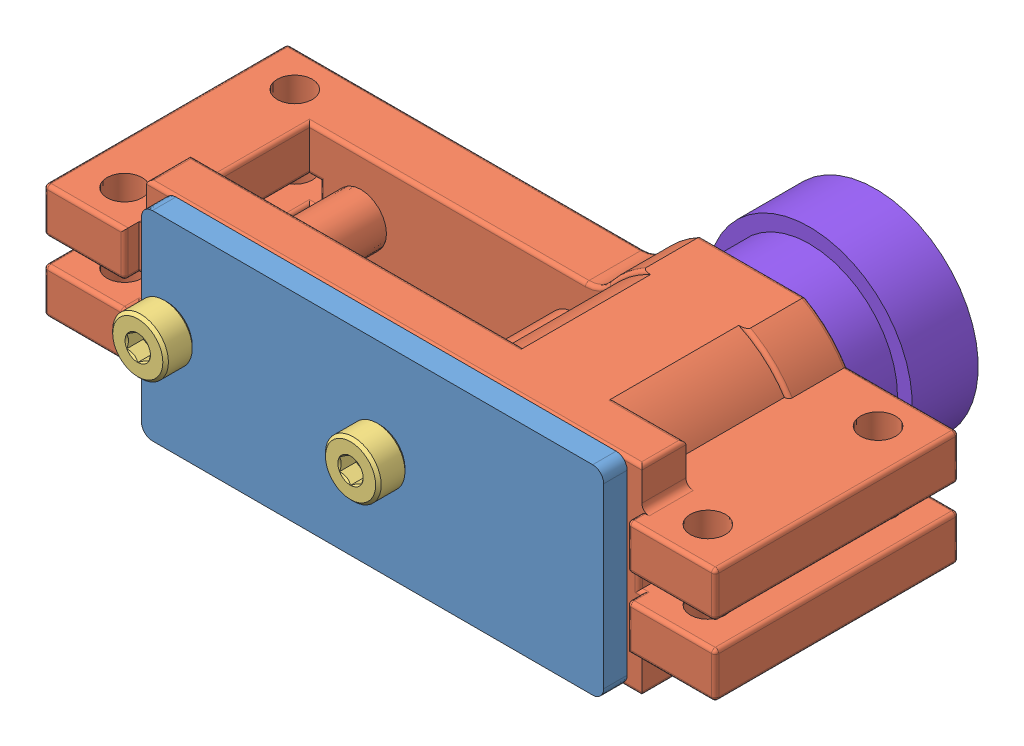
SolidWorks assembly startracker, configuration Default. Lengths in mm.
Overall size (45.75 14.75 27.61).
10 component instances, 8 part files, 55 mates.
Components (placement in the parent):
- startrackerboard-1: startrackerboard [Default] at (0 -0.2 2.3) x (-1 0 0) z (0 0 -1) size (31.5 13.6 1.6)
- startrackerboardmount-1: startrackerboardmount [Default] x (-1 0 0) z (0 0 1) size (45.75 14.75 16.6)
- 92290A850_SUPER-CORROSION-RST 316 SS SCKT HEAD SCREW-1: 92290A850_SUPER-CORROSION-RST 316 SS SCKT HEAD SCREW [92290A850] at (0.5 0 -14.9) x (1 0 0) z (0 0 -1) size (3.8 3.8 20.17)
- 92290A850_SUPER-CORROSION-RST 316 SS SCKT HEAD SCREW-2: 92290A850_SUPER-CORROSION-RST 316 SS SCKT HEAD SCREW [92290A850] at (-14 0 -14.9) x (-1 0 0) z (0 0 -1) size (3.8 3.8 20.17)
- 94150A115_316 STAINLESS STEEL HEX NUT-1: 94150A115_316 STAINLESS STEEL HEX NUT [94150A115] at (0.5 0 -13.05) x (-0.5 0.866025 0) z (0 0 1) size (3.2 3.7 1.58)
- 94150A115_316 STAINLESS STEEL HEX NUT-2: 94150A115_316 STAINLESS STEEL HEX NUT [94150A115] at (-14 0 -13.05) x (0.5 0.866025 0) z (0 0 1) size (3.2 3.7 1.58)
- ILCC48-1: ILCC48 [Default] at (8.75 0 1.5) x (-1 0 0) z (0 0 -1) size (4.8 3.6 0.72)
- knifeedgebaffle-1: knifeedgebaffle [Default] at (8.75 0 -6.425) x (0 1 0) z (1 0 0) size (12 2 12)
- ILCC48_cover-1: ILCC48_cover [Default] at (8.75 0 0.25) x (0 1 0) z (0 0 1) size (7 7 1.25)
- startrackerNEW-1: startrackerNEW [Default] at (8.75 0 -20.925) x (-1 0 0) z (0 0 -1) size (14 14 16)
Mates (geometry in assembly coordinates):
- Parallel1: parallel anti-aligned: plane of startrackerM12-1 through (8.75 0 -7.7) normal (-1 0 0); plane of startrackerboardmount-1 through (22.75 0 9.2082) normal (1 0 0)
- Concentric7: concentric aligned: circle of startrackerboard-1; circle of 92290A850_SUPER-CORROSION-RST 316 SS SCKT HEAD SCREW-1
- Concentric8: concentric aligned: circle of startrackerboard-1; circle of 92290A850_SUPER-CORROSION-RST 316 SS SCKT HEAD SCREW-2
- Parallel2: parallel anti-aligned: plane of startrackerboardmount-1 through (-17 3.9 1.5) normal (0 1 0); plane of 92290A850_SUPER-CORROSION-RST 316 SS SCKT HEAD SCREW-1 through (0.5 0 -14.9) normal (0 -1 0)
- Parallel3: parallel aligned: plane of startrackerboardmount-1 through (-17 3.9 1.5) normal (0 1 0); plane of 92290A850_SUPER-CORROSION-RST 316 SS SCKT HEAD SCREW-2 through (-14 0 -14.9) normal (0 1 0)
- Distance1: distance = 8.6 mm aligned: plane of startrackerM12-1 through (8.75 0 -21.7) normal (0 0 -1); plane of startrackerboardmount-1 through (8.75 0 -13.1) normal (0 0 -1)
- Concentric11: concentric anti-aligned: circle of startrackerM12-1; circle of startrackerboardmount-1
- Coincident17: coincident anti-aligned: plane of startrackerboardmount-1 through (0 0 0) normal (0 -1 0); plane of 91732A183_SPARK PLUG THREAD REPAIR KIT-2 through (0.5 0 1.5) normal (0 1 0)
- Coincident18: coincident anti-aligned: plane of startrackerboardmount-1 through (0 0 1.5) normal (0 0 1); plane of 91732A183_SPARK PLUG THREAD REPAIR KIT-2 through (0.5 0 1.5) normal (0 0 -1)
- Coincident21: coincident: point of startrackerboardmount-1; plane of 91732A183_SPARK PLUG THREAD REPAIR KIT-2 through (0.5 0 1.5) normal (1 0 0)
- Coincident22: coincident anti-aligned: plane of startrackerboardmount-1 through (0 0 1.5) normal (0 0 1); plane of 91732A183_SPARK PLUG THREAD REPAIR KIT-1 through (-14 0 1.5) normal (0 0 -1)
- Coincident23: coincident aligned: plane of startrackerboardmount-1 through (0 0 0) normal (0 -1 0); plane of 91732A183_SPARK PLUG THREAD REPAIR KIT-1 through (-14 0 1.5) normal (0 -1 0)
- Coincident24: coincident: point of startrackerboardmount-1; plane of 91732A183_SPARK PLUG THREAD REPAIR KIT-1 through (-14 0 1.5) normal (-1 0 0)
- Coincident26: coincident anti-aligned: plane of startrackerboardmount-1 through (8.75 0 -13.1) normal (0 0 -1); plane of 91732A183_SPARK PLUG THREAD REPAIR KIT-3 through (0.5 0 -13.1) normal (0 0 1)
- Coincident27: coincident: point of startrackerboardmount-1; plane of 91732A183_SPARK PLUG THREAD REPAIR KIT-3 through (0.5 0 -13.1) normal (-1 0 0)
- Coincident28: coincident: point of startrackerboardmount-1; plane of 91732A183_SPARK PLUG THREAD REPAIR KIT-3 through (0.5 0 -13.1) normal (0 1 0)
- Parallel4: parallel anti-aligned: plane of startrackerboardmount-1 through (-20 -3.9 1.5) normal (0 -1 0); plane of 91732A183_SPARK PLUG THREAD REPAIR KIT-3 through (0.5 0 -13.1) normal (0 1 0)
- Coincident29: coincident anti-aligned: plane of startrackerboardmount-1 through (8.75 0 -13.1) normal (0 0 -1); plane of 91732A183_SPARK PLUG THREAD REPAIR KIT-4 through (-14 0 -13.1) normal (0 0 1)
- Coincident30: coincident: point of startrackerboardmount-1; plane of 91732A183_SPARK PLUG THREAD REPAIR KIT-4 through (-14 0 -13.1) normal (-1 0 0)
- Coincident31: coincident: point of startrackerboardmount-1; plane of 91732A183_SPARK PLUG THREAD REPAIR KIT-4 through (-14 0 -13.1) normal (0 1 0)
- Parallel5: parallel anti-aligned: plane of startrackerboardmount-1 through (-20 -3.9 1.5) normal (0 -1 0); plane of 91732A183_SPARK PLUG THREAD REPAIR KIT-4 through (-14 0 -13.1) normal (0 1 0)
- Coincident32: coincident anti-aligned: plane of startrackerboardmount-1 through (0 0 0) normal (0 -1 0)
- Coincident33: coincident anti-aligned: plane of startrackerboardmount-1 through (0 0 0) normal (-1 0 0)
- Coincident34: coincident aligned: plane of startrackerboardmount-1 through (0 0 0) normal (0 0 1)
- Coincident35: coincident anti-aligned: plane of startrackerboard-1 through (15 5.85 1.5) normal (0 0 -1); plane of startrackerboardmount-1 through (0 0 1.5) normal (0 0 1)
- Coincident36: coincident aligned: plane of startrackerboard-1 through (15 6.6 1.5) normal (0 1 0); plane of startrackerboardmount-1 through (-17 6.6 -14.1) normal (0 1 0)
- Coincident38: coincident anti-aligned: plane of startrackerboard-1 through (15 5.85 3.1) normal (0 0 1); plane of 92290A850_SUPER-CORROSION-RST 316 SS SCKT HEAD SCREW-2 through (-14 0 3.1) normal (0 0 -1)
- Coincident39: coincident anti-aligned: plane of startrackerboard-1 through (15 5.85 3.1) normal (0 0 1); plane of 92290A850_SUPER-CORROSION-RST 316 SS SCKT HEAD SCREW-1 through (0.5 0 3.1) normal (0 0 -1)
- Coincident40: coincident aligned: plane of startrackerboard-1 through (0 -0.2 2.3) normal (-1 0 0); plane of startrackerboardmount-1 through (0 0 0) normal (-1 0 0)
- Concentric12: concentric anti-aligned: circle of 92290A850_SUPER-CORROSION-RST 316 SS SCKT HEAD SCREW-1; circle of 94150A115_316 STAINLESS STEEL HEX NUT-1
- Concentric13: concentric anti-aligned: circle of 92290A850_SUPER-CORROSION-RST 316 SS SCKT HEAD SCREW-2; circle of 94150A115_316 STAINLESS STEEL HEX NUT-2
- Coincident42: coincident anti-aligned: plane of startrackerboardmount-1 through (0 0 -12.4) normal (0 0 -1); plane of 94150A115_316 STAINLESS STEEL HEX NUT-1 through (0.5 -1.8475 -12.4) normal (0 0 1)
- Parallel6: parallel aligned: plane of 94150A115_316 STAINLESS STEEL HEX NUT-1 through (-1.1 0.9238 -12.4) normal (-1 0 0); plane of startrackerboardmount-1 through (-23 0 16.7315) normal (-1 0 0)
- Parallel7: parallel aligned: plane of 94150A115_316 STAINLESS STEEL HEX NUT-2 through (-15.6 0.9238 -12.4) normal (-1 0 0); plane of startrackerboardmount-1 through (-23 0 16.7315) normal (-1 0 0)
- Coincident43: coincident aligned: plane of startrackerM12-1 through (8.75 0 -7.7) normal (-1 0 0); plane of ILCC48-1 through (8.75 0 1.5) normal (-1 0 0)
- Coincident44: coincident anti-aligned: plane of startrackerM12-1 through (8.75 0 -7.7) normal (0 -1 0); plane of ILCC48-1 through (8.75 0 1.5) normal (0 1 0)
- Coincident45: coincident anti-aligned: plane of startrackerboard-1 through (15 5.85 1.5) normal (0 0 -1); plane of ILCC48-1 through (8.75 0 1.5) normal (0 0 1)
- Coincident46: coincident anti-aligned: plane of startrackerM12-1 through (8.75 0 -7.7) normal (0 -1 0); plane of knifeedgebaffle-1 through (8.75 0 -6.425) normal (0 1 0)
- Coincident47: coincident anti-aligned: plane of startrackerM12-1 through (8.75 0 -7.7) normal (-1 0 0); plane of knifeedgebaffle-1 through (8.75 0 -6.425) normal (1 0 0)
- Coincident48: coincident anti-aligned: plane of startrackerboardmount-1 through (8.75 0 -4.425) normal (0 0 -1); plane of knifeedgebaffle-1 through (8.75 0 -4.425) normal (0 0 1)
- Coincident49: coincident anti-aligned: plane of startrackerM12-1 through (8.75 0 -7.7) normal (0 -1 0); plane of ILCC48_cover-1 through (8.75 0 0.25) normal (0 1 0)
- Coincident50: coincident aligned: plane of startrackerM12-1 through (8.75 0 -7.7) normal (-1 0 0); plane of ILCC48_cover-1 through (8.75 0 0.25) normal (-1 0 0)
- Coincident52: coincident aligned: plane of ILCC48-1 through (8.75 0 1.5) normal (0 0 1); plane of ILCC48_cover-1 through (8.75 0 1.5) normal (0 0 1)
- Coincident53: coincident anti-aligned: circle of startrackerboardmount-1; circle of knifeedgebaffle-1
- Coincident54: coincident aligned: plane of knifeedgebaffle-1 through (8.75 0 -6.425) normal (0 1 0)
- Coincident55: coincident aligned: plane of knifeedgebaffle-1 through (8.75 0 -6.425) normal (0 1 0); plane of ILCC48_cover-1 through (8.75 0 0.25) normal (0 1 0)
- Coincident56: coincident anti-aligned: plane of knifeedgebaffle-1 through (8.75 0 -6.425) normal (1 0 0); plane of ILCC48_cover-1 through (8.75 0 0.25) normal (-1 0 0)
- Coincident58: coincident aligned: plane of startrackerNEW-1 through (8.75 0 -20.925) normal (0 1 0)
- Distance2: distance = 7.2 mm anti-aligned: plane of startrackerNEW-1 through (8.75 6 -6.425) normal (0 0 1); plane of ILCC48-1 through (8.75 0 0.775) normal (0 0 -1)
- Concentric15: concentric anti-aligned: circle of startrackerboardmount-1; circle of startrackerNEW-1
- Concentric16: concentric anti-aligned: circle of startrackerboard-1; circle of 92290A850_SUPER-CORROSION-RST 316 SS SCKT HEAD SCREW-2
- Concentric17: concentric anti-aligned: circle of startrackerboard-1; circle of 92290A850_SUPER-CORROSION-RST 316 SS SCKT HEAD SCREW-1
- Coincident59: coincident anti-aligned: plane of startrackerboardmount-1 through (0 0 -12.4) normal (0 0 -1); plane of 94150A115_316 STAINLESS STEEL HEX NUT-2 through (-15.6 -0.9238 -12.4) normal (0 0 1)
- Coincident60: coincident aligned: plane of ILCC48-1 through (8.75 0 1.5) normal (0 1 0); plane of knifeedgebaffle-1 through (8.75 0 -6.425) normal (0 1 0)
- Coincident61: coincident anti-aligned: plane of ILCC48-1 through (8.75 0 1.5) normal (-1 0 0); plane of knifeedgebaffle-1 through (8.75 0 -6.425) normal (1 0 0)
